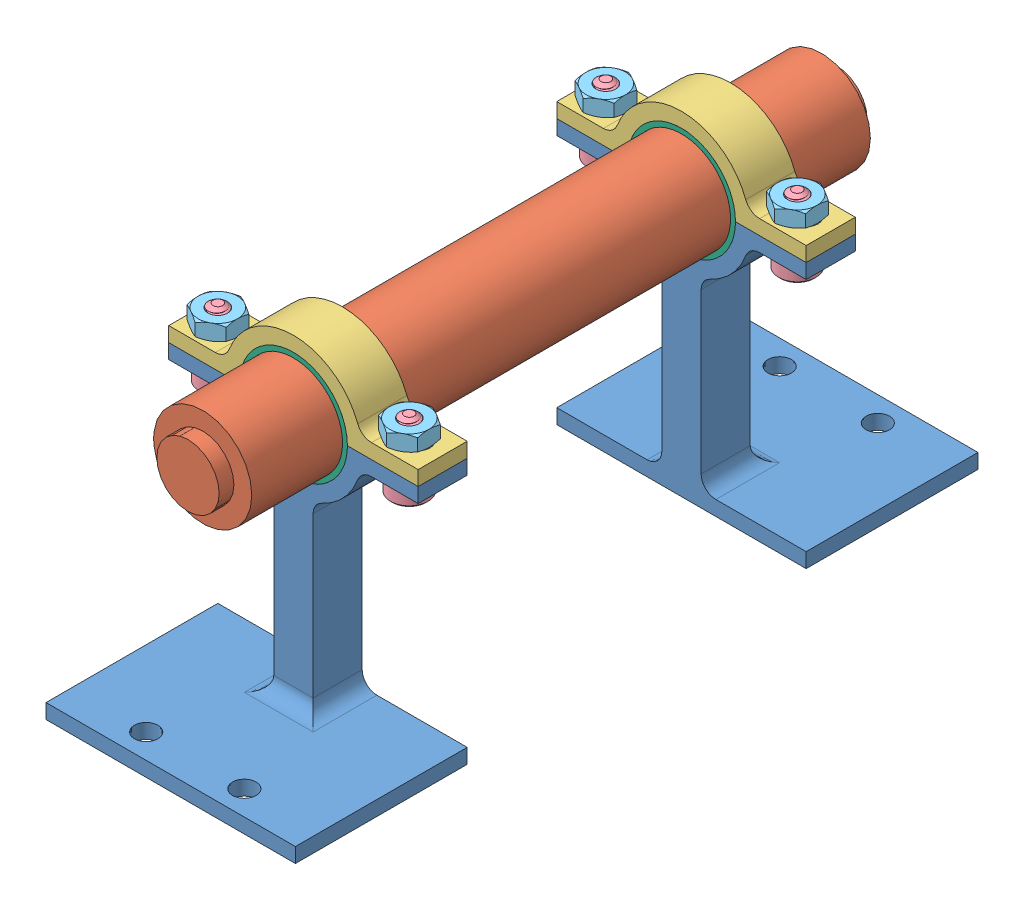
SolidWorks assembly Linear_Tall, configuration Default. Lengths in mm.
Overall size (25.9 34 69.52).
15 component instances, 6 part files, 21 mates.
Components (placement in the parent):
- Bracket_Base_Tall-1: Bracket_Base_Tall [Default] at (-39.2977 11.7306 21.939) size (25.4 27 17.5)
- Bracket_Base_Tall-2: Bracket_Base_Tall [Default] at (-39.2977 11.7306 -17.581) x (-1 0 0) z (0 0 -1) size (25.4 27 17.5)
- Linear_Magnetorquer-1: Linear_Magnetorquer [Default] at (-39.2977 11.7306 2.179) x (-1 0 0) z (0 0 1) size (10 10 66)
- Bracket_Top-1: Bracket_Top [Default] at (-39.2977 11.7306 21.939) x (-1 0 0) z (0 0 1) size (25.4 7 5)
- Bracket_Top-2: Bracket_Top [Default] at (-39.2977 11.7306 -17.581) x (-1 0 0) z (0 0 1) size (25.4 7 5)
- 92290A012_TYPE 316 SS SOCKET HEAD CAP SCREW-1: 92290A012_TYPE 316 SS SOCKET HEAD CAP SCREW [92290A012] at (-49.4977 15.2306 21.939) x (1 0 0) z (0 1 0) size (3.8 3.8 7.44)
- 92290A012_TYPE 316 SS SOCKET HEAD CAP SCREW-3: 92290A012_TYPE 316 SS SOCKET HEAD CAP SCREW [92290A012] at (-49.4977 15.2306 -17.581) x (1 0 0) z (0 1 0) size (3.8 3.8 7.44)
- 92290A012_TYPE 316 SS SOCKET HEAD CAP SCREW-4: 92290A012_TYPE 316 SS SOCKET HEAD CAP SCREW [92290A012] at (-29.9977 15.2306 21.939) x (1 0 0) z (0 1 0) size (3.8 3.8 7.44)
- 92290A012_TYPE 316 SS SOCKET HEAD CAP SCREW-5: 92290A012_TYPE 316 SS SOCKET HEAD CAP SCREW [92290A012] at (-29.9977 15.2306 -17.581) x (1 0 0) z (0 1 0) size (3.8 3.8 7.44)
- 91828A111_TYPE 18-8 STAINLESS STEEL HEX NUT-1: 91828A111_TYPE 18-8 STAINLESS STEEL HEX NUT [91828A111] at (-49.4977 14.0306 21.939) x (-0.5 0 0.866025) z (0 -1 0) size (4 4.62 1.83)
- 91828A111_TYPE 18-8 STAINLESS STEEL HEX NUT-2: 91828A111_TYPE 18-8 STAINLESS STEEL HEX NUT [91828A111] at (-29.9977 14.0306 21.939) x (-0.5 0 0.866025) z (0 -1 0) size (4 4.62 1.83)
- 91828A111_TYPE 18-8 STAINLESS STEEL HEX NUT-3: 91828A111_TYPE 18-8 STAINLESS STEEL HEX NUT [91828A111] at (-49.4977 14.0306 -17.581) x (-0.5 0 0.866025) z (0 -1 0) size (4 4.62 1.83)
- 91828A111_TYPE 18-8 STAINLESS STEEL HEX NUT-4: 91828A111_TYPE 18-8 STAINLESS STEEL HEX NUT [91828A111] at (-29.9977 14.0306 -17.581) x (-0.5 0 0.866025) z (0 -1 0) size (4 4.62 1.83)
- Rubber_grip-1: Rubber_grip [Default] at (-39.2977 11.7306 19.439) size (11 11 5)
- Rubber_grip-2: Rubber_grip [Default] at (-39.2977 11.7306 -20.081) size (11 11 5)
Mates (geometry in assembly coordinates):
- Distance1: distance = 34.52 mm anti-aligned: plane of Bracket_Base_Tall-2 through (-39.2977 11.7306 -15.081) normal (0 0 1); plane of Bracket_Base_Tall-1 through (-39.2977 11.7306 19.439) normal (0 0 -1)
- Concentric1: concentric anti-aligned: cylinder of Bracket_Base_Tall-2 through (-39.2977 11.7306 -20.081) axis (0 0 1) radius 5.5; cylinder of Linear_Magnetorquer-1 through (-39.2977 11.7306 33.679) axis (0 0 -1) radius 5
- Coincident5: coincident anti-aligned: circle of Bracket base tall-1; circle of Bracket top-1
- Coincident6: coincident anti-aligned: circle of Bracket base tall-2; circle of Bracket top-2
- Concentric2: concentric anti-aligned: circle of Bracket base tall-2; circle of Bracket top-2
- Concentric3: concentric anti-aligned: circle of Bracket base tall-1; circle of Bracket top-1
- Coincident12: coincident anti-aligned: plane of Bracket_Base_Tall-1 through (-51.9977 10.2306 24.439) normal (0 -1 0); plane of 92290A012_TYPE 316 SS SOCKET HEAD CAP SCREW-1 through (-49.4977 10.2306 21.939) normal (0 1 0)
- Concentric9: concentric aligned: circle of Bracket base tall-1; circle of 92290A012_TYPE 316 SS SOCKET HEAD CAP SCREW-1
- Parallel1: parallel anti-aligned: plane of Linear_Magnetorquer-1 through (-39.2977 11.7306 2.179) normal (-1 0 0)
- Coincident14: coincident anti-aligned: plane of Bracket_Top-1 through (-51.9977 13.2306 24.439) normal (0 1 0); plane of 91828A111_TYPE 18-8 STAINLESS STEEL HEX NUT-1 through (-49.4977 13.2306 19.6296) normal (0 -1 0)
- Concentric13: concentric anti-aligned: circle of Bracket top-1; circle of 91828A111_TYPE 18-8 STAINLESS STEEL HEX NUT-1
- Parallel2: parallel aligned: plane of 91828A111_TYPE 18-8 STAINLESS STEEL HEX NUT-1 through (-51.4977 13.2306 23.0937) normal (-1 0 0); plane of Bracket_Base_Tall-1 through (-51.9977 11.7306 24.439) normal (-1 0 0)
- Coincident18: coincident aligned: plane of Bracket_Base_Tall-1 through (-39.2977 -15.2694 21.939) normal (0 -1 0); plane of Bracket_Base_Tall-2 through (-39.2977 -15.2694 -17.581) normal (0 -1 0)
- Coincident19: coincident aligned: plane of Bracket_Base_Tall-1 through (-26.5977 -15.2694 19.439) normal (1 0 0); plane of Bracket_Base_Tall-2 through (-26.5977 -15.2694 -15.081) normal (1 0 0)
- Distance5: distance = 10.74 mm aligned: plane of Bracket_Base_Tall-2 through (-39.2977 11.7306 -20.081) normal (0 0 -1); plane of Linear_Magnetorquer-1 through (-39.2977 11.7306 -30.821) normal (0 0 -1)
- Concentric14: concentric aligned: cylinder of Linear_Magnetorquer-1 through (-39.2977 11.7306 33.679) axis (0 0 -1) radius 5; cylinder of rubber_grip-1 through (-39.2977 11.7306 24.439) axis (0 0 -1) radius 5
- Concentric15: concentric aligned: cylinder of Linear_Magnetorquer-1 through (-39.2977 11.7306 33.679) axis (0 0 -1) radius 5; cylinder of rubber_grip-2 through (-39.2977 11.7306 -15.081) axis (0 0 -1) radius 5
- Coincident21: coincident aligned: plane of Bracket_Top-2 through (-39.2977 11.7306 -15.081) normal (0 0 1); plane of rubber_grip-2 through (-39.2977 11.7306 -15.081) normal (0 0 1)
- Coincident22: coincident aligned: plane of Bracket_Base_Tall-1 through (-39.2977 11.7306 19.439) normal (0 0 -1); plane of rubber_grip-1 through (-39.2977 11.7306 19.439) normal (0 0 -1)
- Parallel4: parallel aligned: plane of rubber_grip-2 through (-39.2977 11.7306 -20.081) normal (0 1 0)
- Coincident24: coincident aligned: plane of Bracket_Base_Tall-1 through (-39.2977 11.7306 21.939) normal (0 1 0); plane of rubber_grip-1 through (-39.2977 11.7306 19.439) normal (0 1 0)
